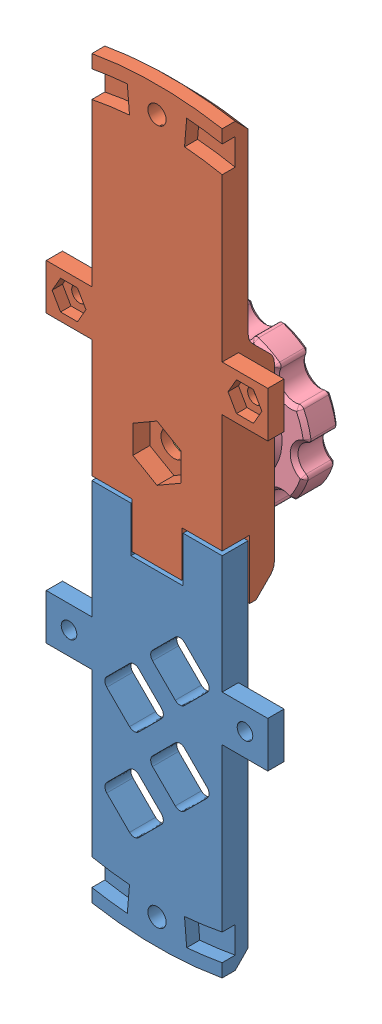
SolidWorks assembly ClampThingy, configuration Default. Lengths in mm.
Overall size (43.18 145.58 21.82).
4 component instances, 4 part files, 7 mates.
Components (placement in the parent):
- MountyThingyTop2-1: MountyThingyTop2 [Default] at (8.374 61.2013 54.5171) size (43.18 72.39 10.16)
- MountyThingyTop1-1: MountyThingyTop1 [Default] at (8.374 62.0032 54.5171) size (43.18 83.94 10.16)
- Wedge-1: Wedge [Default] at (-0.262 71.7622 52.1294) x (0 -1 0) z (1 0 0) size (30.86 5.08 17.27)
- ThumbScrew-1: ThumbScrew [Default] at (8.374 72.1632 45.3984) x (-0.6464 0.762999 0) z (0 0 -1) size (29.63 29.63 12.45)
Mates (geometry in assembly coordinates):
- Distance1: distance = 0.254 mm anti-aligned: plane of Wedge-1 through (-0.262 71.7622 52.1294) normal (-1 0 0); plane of MountyThingyTop1-1 through (-0.516 62.0032 54.5171) normal (1 0 0)
- Coincident6: coincident anti-aligned: plane of MountyThingyTop1-1 through (-0.516 82.189 61.8642) normal (0 -0.939693 -0.34202); plane of Wedge-1 through (17.01 87.5812 47.0494) normal (0 0.939693 0.34202)
- Concentric1: concentric aligned: cylinder of MountyThingyTop1-1 through (8.374 72.1632 54.5171) axis (0 0 1) radius 2.54; circle of ThumbScrew-1
- Coincident7: coincident anti-aligned: plane of Wedge-1 through (8.374 69.8572 50.2244) normal (0 0 -1); plane of ThumbScrew-1 through (4.2694 77.0082 50.2244) normal (0 0 1)
- Coincident8: coincident anti-aligned: plane of MountyThingyTop2-1 through (17.137 58.9584 55.3334) normal (0 0.939693 -0.34202); plane of Wedge-1 through (17.01 57.7922 52.1294) normal (0 -0.939693 0.34202)
- Coincident9: coincident aligned: plane of MountyThingyTop2-1 through (8.374 61.2013 59.5971) normal (0 0 1); plane of MountyThingyTop1-1 through (8.374 62.0032 59.5971) normal (0 0 1)
- Coincident10: coincident aligned: plane of MountyThingyTop2-1 through (-4.326 61.2013 59.5971) normal (-1 0 0); plane of MountyThingyTop1-1 through (-4.326 62.0032 59.5971) normal (-1 0 0)
